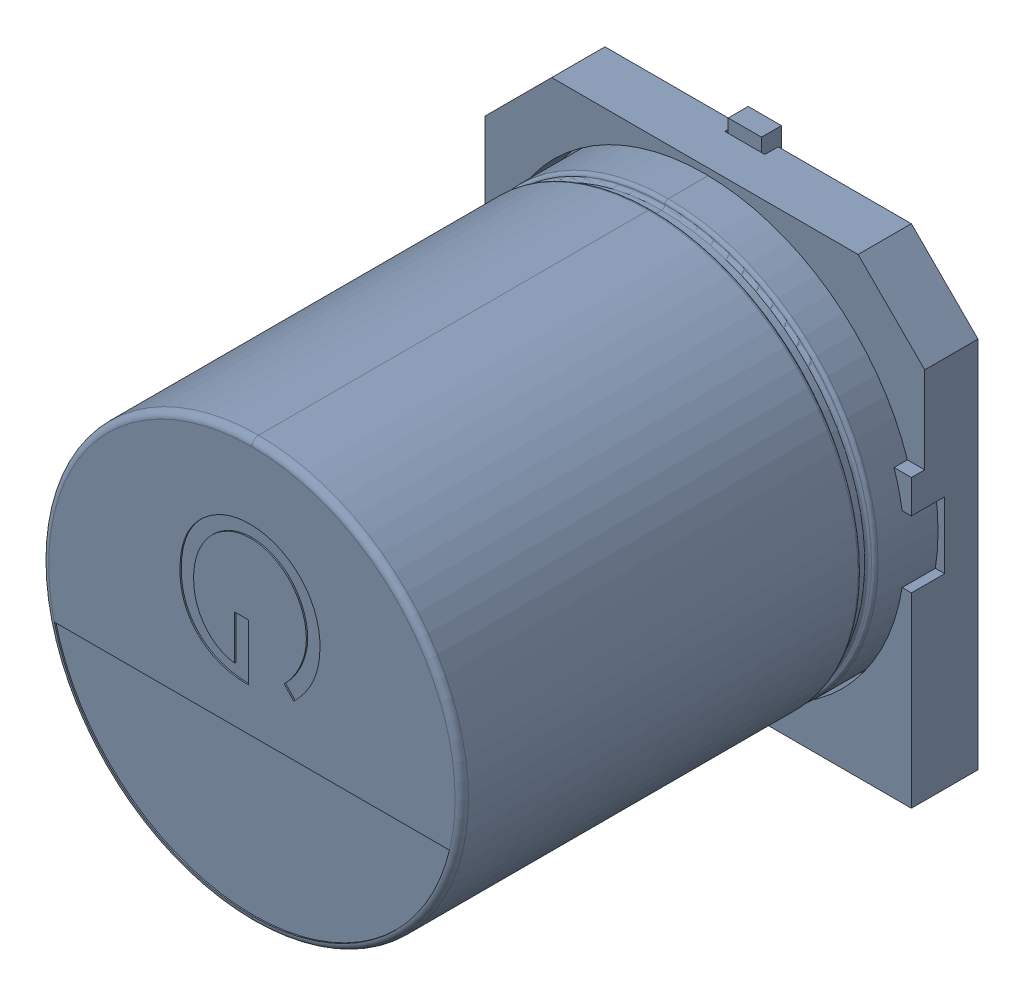
SolidWorks assembly C7, configuration 默认. Lengths in mm.
Overall size (6.6 7 7.7).
2 component instances, 1 part files, 0 mates.
Components (placement in the parent):
- SL-G-1: SL-G [默认] at (22.8601 18.1609 0) x (0 -1 0) z (0 0 1) size (7 6.6 7.7)
  - SL-G-1: SL-G [默认] at origin size (7 6.6 7.7)
